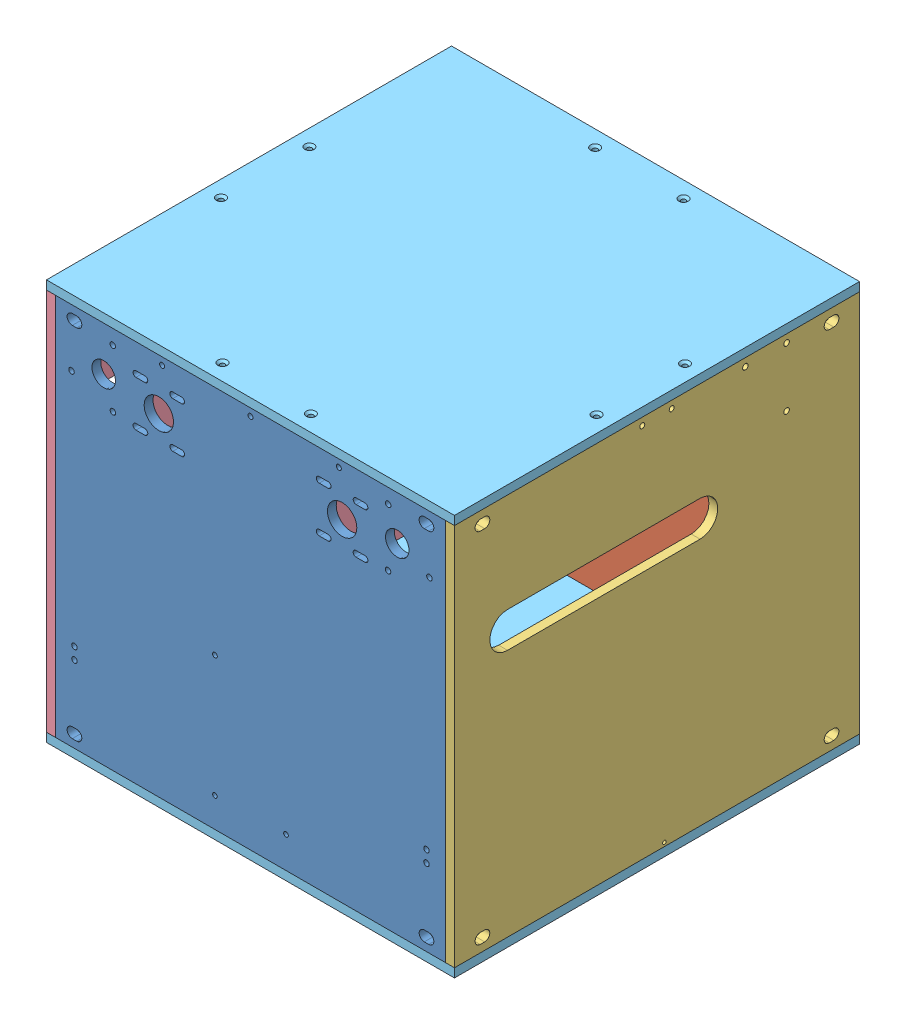
SolidWorks assembly Carcassa, configuration Predeterminado. Lengths in mm.
Overall size (277 272 275).
6 component instances, 5 part files, 14 mates.
Components (placement in the parent):
- carcassa darrere-1: carcassa darrere [Predeterminado] at (-2.5107 8.7875 261.5) size (265 260 6)
- carcassa davant-1: carcassa davant [Predeterminado] at (-2.5107 8.7875 -7.5) size (265 260 6)
- carcassa dreta-1: carcassa dreta [Predeterminado] at (135.9893 8.7875 124) x (0 0 -1) z (1 0 0) size (275 260 6)
- carcassa esquerra-1: carcassa esquerra [Predeterminado] at (-135.0107 8.7875 124) x (0 0 -1) z (1 0 0) size (275 260 6)
- carcassa tapa-1: carcassa tapa [debajo] at (-2.5107 144.7875 124) x (-1 0 0) z (0 1 0) size (277 275 6)
- carcassa tapa-2: carcassa tapa [Predeterminado] at (-2.5107 -121.2125 124) x (-1 0 0) z (0 1 0) size (277 275 6)
Mates (geometry in assembly coordinates):
- Coincidente1: coincident anti-aligned: line of carcassa esquerra-1 through (-135.0107 -121.2125 261.5) axis (0 0 -1); line of carcassa darrere-1 through (-135.0107 -121.2125 255.5) axis (0 0 1)
- Perpendicular1: perpendicular: plane of carcassa darrere-1 through (-2.5107 8.7875 261.5) normal (0 0 1); plane of carcassa esquerra-1 through (-135.0107 8.7875 124) normal (1 0 0)
- Coincidente5: coincident aligned: plane of carcassa darrere-1 through (-135.0107 -121.2125 255.5) normal (0 -1 0); plane of carcassa esquerra-1 through (-141.0107 -121.2125 261.5) normal (0 -1 0)
- Coincidente7: coincident aligned: line of carcassa darrere-1 through (-135.0107 -121.2125 261.5) axis (1 0 0); line of carcassa esquerra-1 through (-141.0107 -121.2125 261.5) axis (1 0 0)
- Coincidente8: coincident aligned: line of carcassa davant-1 through (-135.0107 -121.2125 -13.5) axis (1 0 0); line of carcassa esquerra-1 through (-141.0107 -121.2125 -13.5) axis (1 0 0)
- Coincidente10: coincident anti-aligned: line of carcassa davant-1 through (-135.0107 -121.2125 -13.5) axis (0 0 1); line of carcassa esquerra-1 through (-135.0107 -121.2125 261.5) axis (0 0 -1)
- Coincidente11: coincident aligned: line of carcassa davant-1 through (129.9893 -121.2125 -13.5) axis (0 1 0); line of carcassa dreta-1 through (129.9893 -121.2125 -13.5) axis (0 1 0)
- Coincidente13: coincident anti-aligned: line of carcassa darrere-1 through (129.9893 -121.2125 255.5) axis (0 0 1); line of carcassa dreta-1 through (129.9893 -121.2125 261.5) axis (0 0 -1)
- Coincidente2804: coincident aligned: plane of carcassa tapa-2 through (135.9893 -127.2125 -13.5) normal (0 0 -1); plane of carcassa tapa-1 through (135.9893 138.7875 -13.5) normal (0 0 -1)
- Coincidente2805: coincident aligned: plane of carcassa tapa-2 through (-141.0107 -127.2125 261.5) normal (-1 0 0); plane of carcassa tapa-1 through (-141.0107 138.7875 261.5) normal (-1 0 0)
- Coincidente2806: coincident anti-aligned: plane of carcassa esquerra-1 through (-141.0107 138.7875 261.5) normal (0 1 0); plane of carcassa tapa-1 through (-2.5107 138.7875 124) normal (0 -1 0)
- Coincidente147: coincident anti-aligned: plane of carcassa dreta-1 through (129.9893 -121.2125 261.5) normal (0 -1 0); plane of carcassa tapa-2 through (-2.5107 -121.2125 124) normal (0 1 0)
- Coincidente148: coincident aligned: plane of carcassa darrere-1 through (-2.5107 8.7875 261.5) normal (0 0 1); plane of carcassa tapa-2 through (135.9893 -127.2125 261.5) normal (0 0 1)
- Coincidente149: coincident aligned: plane of carcassa esquerra-1 through (-141.0107 8.7875 124) normal (-1 0 0); plane of carcassa tapa-2 through (-141.0107 -127.2125 261.5) normal (-1 0 0)
